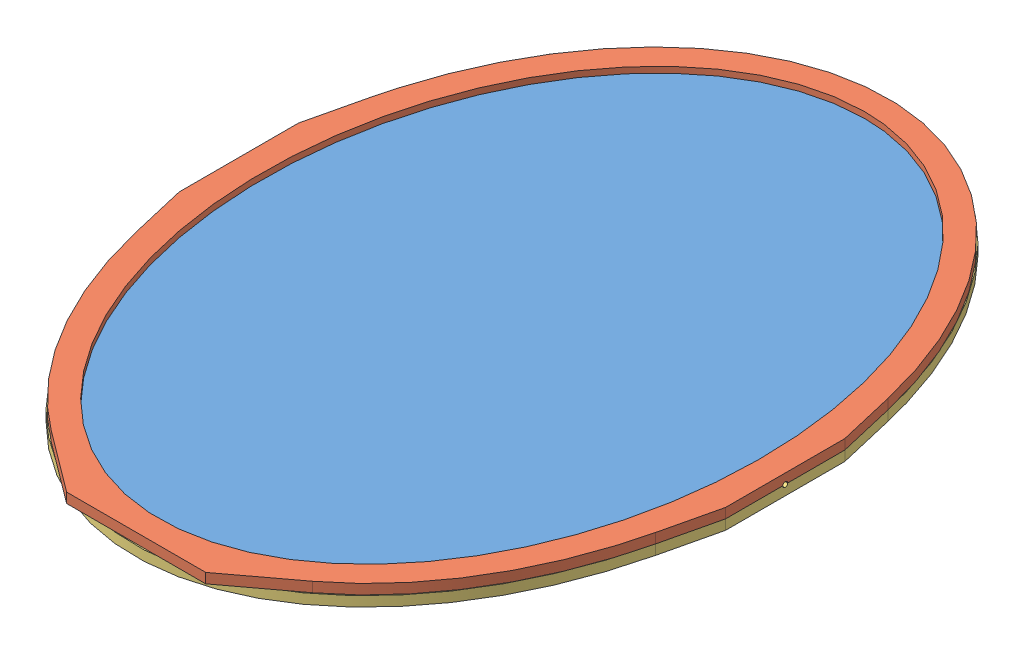
SolidWorks assembly Primary Mirror Assembly, configuration Default. Lengths in mm.
Overall size (550 20 760).
4 component instances, 3 part files, 3 mates.
Components (placement in the parent):
- Mirror Assembly-1: Mirror Assembly [Default] at origin size (550 20 760)
  - Mirror-1: Mirror [Default] at origin size (520 4 730)
  - Mirror Front-1: Mirror Front [Default] at origin size (550 10 756.61)
  - Mirror Back-1: Mirror Back [Default] x (-1 0 0) z (0 0 1) size (550 10 760)
Mates (geometry in assembly coordinates):
- Coincident2: coincident aligned: plane of ? through (0 0 0) normal (0 0 1); plane of assembly through (0 0 0) normal (0 0 1)
- Coincident3: coincident aligned: plane of ? through (0 0 0) normal (0 1 0); plane of assembly through (0 0 0) normal (0 1 0)
- Coincident4: coincident aligned: plane of ? through (0 0 0) normal (1 0 0); plane of assembly through (0 0 0) normal (1 0 0)
